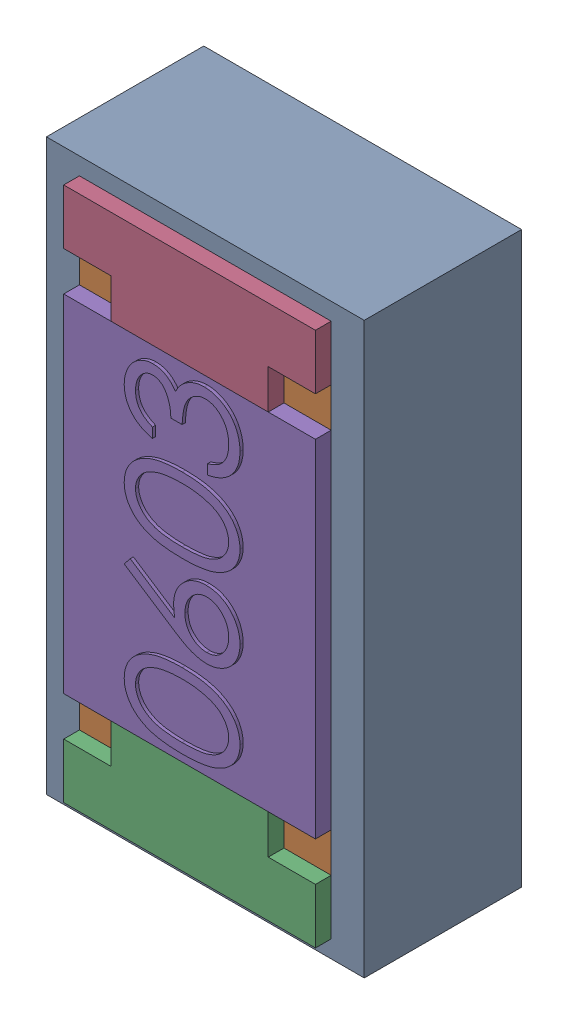
SolidWorks assembly SB1, configuration Default. Lengths in mm.
Overall size (1.01 1.81 0.56).
3 component instances, 2 part files, 0 mates.
Components (placement in the parent):
- 1088884704-1: 1088884704 [Default] at (15.2 27.25 0) size (1.01 1.81 0.5)
  - Extruded-0-1: Extruded-0 [Default] at origin size (1.01 1.81 0.5)
- R0603-1: R0603 [Default] at (15.1999 27.2501 0) x (0 1 0) z (1 0 0) size (1.7 0.56 0.8)
